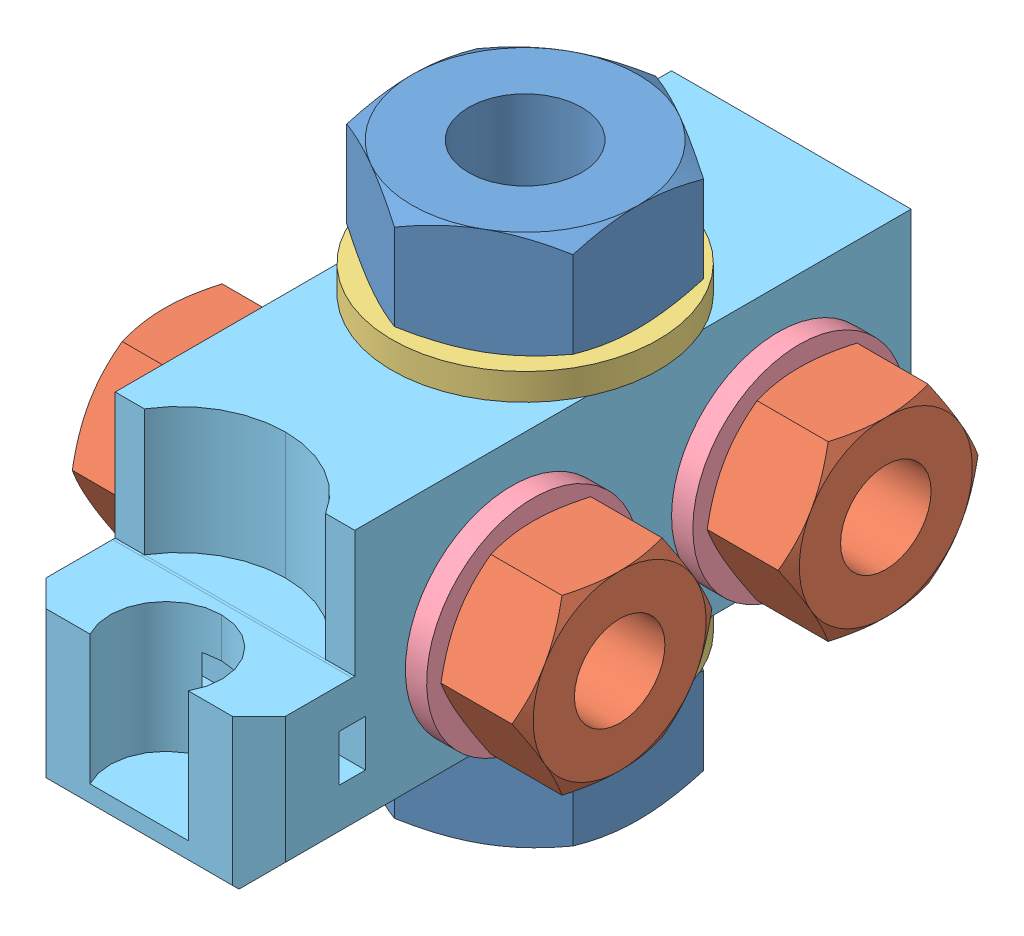
SolidWorks assembly Assembly y-corners, configuration Valor predeterminado. Lengths in mm.
Overall size (34.2 40 50.08).
13 component instances, 5 part files, 25 mates.
Components (placement in the parent):
- Nut DIN 934 - M10-1: Nut DIN 934 - M10 [Valor predeterminado] at (-49.2679 6.8342 8.2968) x (0 -1 0) z (0.866025 0 0.5) size (8 17 19.63)
- Nut DIN 934 - M8-1: Nut DIN 934 - M8 [Valor predeterminado] at (-63.1179 -10.1658 -1.7032) x (1 0 0) z (0 0.527567 0.849514) size (6.5 13 15.01)
- Washer DIN 125A - M10-1: Washer DIN 125A - M10 [Valor predeterminado] at (-49.2679 -19.1658 8.2968) x (0 -1 0) z (0.326363 0 0.945245) size (2 20 20)
- Washer DIN 125A - M8-1: Washer DIN 125A - M8 [Valor predeterminado] at (-40.2679 -10.1658 -1.7032) x (1 0 0) z (0 -0.550558 0.834797) size (1.6 16 16)
- Washer DIN 125A - M10-2: Washer DIN 125A - M10 [Valor predeterminado] at (-49.2679 2.8342 8.2968) x (0 -1 0) z (0.326363 0 0.945245) size (2 20 20)
- Washer DIN 125A - M8-2: Washer DIN 125A - M8 [Valor predeterminado] at (-59.8679 -10.1658 -1.7032) x (1 0 0) z (0 0.106248 0.99434) size (1.6 16 16)
- Nut DIN 934 - M10-2: Nut DIN 934 - M10 [Valor predeterminado] at (-49.2679 -25.1658 8.2968) x (0 -1 0) z (0.866025 0 0.5) size (8 17 19.63)
- Washer DIN 125A - M8-3: Washer DIN 125A - M8 [Valor predeterminado] at (-59.8679 -10.1658 18.2968) x (1 0 0) z (0 0.258445 0.966026) size (1.6 16 16)
- Washer DIN 125A - M8-4: Washer DIN 125A - M8 [Valor predeterminado] at (-40.2679 -10.1658 18.2968) x (1 0 0) z (0 -0.676712 0.736248) size (1.6 16 16)
- Nut DIN 934 - M8-2: Nut DIN 934 - M8 [Valor predeterminado] at (-63.1179 -10.1658 18.2968) x (1 0 0) z (0 0.866025 0.5) size (6.5 13 15.01)
- Nut DIN 934 - M8-3: Nut DIN 934 - M8 [Valor predeterminado] at (-35.4179 -10.1658 18.2968) x (1 0 0) z (0 0.866025 0.5) size (6.5 13 15.01)
- Nut DIN 934 - M8-4: Nut DIN 934 - M8 [Valor predeterminado] at (-35.4179 -10.1658 -1.7032) size (6.5 13 15.01)
- y-corners-2: y-corners [Valor predeterminado] at (-49.2679 0.8342 -11.7032) size (18 22 49)
Mates (geometry in assembly coordinates):
- Coincidente3: coincident: plane of assembly; plane of assembly; plane of Washer DIN 125A - M10-1 through (-49.2679 -21.1658 8.2968) normal (0 -1 0); plane of Nut DIN 934 - M10-2 through (-57.7679 -21.1658 -6.4256) normal (0 1 0)
- Coincidente4: coincident: plane of assembly; plane of assembly; plane of Nut DIN 934 - M10-1 through (-57.7679 2.8342 -6.4256) normal (0 -1 0); plane of Washer DIN 125A - M10-2 through (-49.2679 2.8342 8.2968) normal (0 1 0)
- Coincidente11: coincident: plane of assembly; plane of assembly; plane of Nut DIN 934 - M8-1 through (-59.8679 -14.1255 -8.0792) normal (1 0 0); plane of Washer DIN 125A - M8-2 through (-59.8679 -10.1658 -1.7032) normal (-1 0 0)
- Coincidente12: coincident: plane of assembly; plane of assembly; plane of Washer DIN 125A - M8-3 through (-59.8679 -10.1658 18.2968) normal (-1 0 0); plane of Nut DIN 934 - M8-2 through (-59.8679 -16.6658 14.5441) normal (1 0 0)
- Coincidente13: coincident: plane of assembly; plane of assembly; plane of Washer DIN 125A - M8-1 through (-38.6679 -10.1658 -1.7032) normal (1 0 0); plane of Nut DIN 934 - M8-4 through (-38.6679 -10.1658 -9.2087) normal (-1 0 0)
- Coincidente14: coincident: plane of assembly; plane of assembly; plane of Washer DIN 125A - M8-4 through (-38.6679 -10.1658 18.2968) normal (1 0 0); plane of Nut DIN 934 - M8-3 through (-38.6679 -16.6658 14.5441) normal (-1 0 0)
- Concêntrico1: concentric: cylinder of assembly; cylinder of assembly; cylinder of Washer DIN 125A - M8-3 through (-58.2679 -10.1658 18.2968) axis (-1 0 0) radius 4.2; cylinder of Nut DIN 934 - M8-2 through (-59.8679 -10.1658 18.2968) axis (-1 0 0) radius 3.4
- Concêntrico3: concentric: cylinder of assembly; cylinder of assembly; cylinder of Nut DIN 934 - M8-2 through (-59.8679 -10.1658 18.2968) axis (-1 0 0) radius 3.4; cylinder of y-corners-2 through (-65.2679 -10.1658 18.2968) axis (1 0 0) radius 4.4
- Coincidente15: coincident: plane of assembly; plane of assembly; plane of Washer DIN 125A - M8-3 through (-58.2679 -10.1658 18.2968) normal (1 0 0); plane of y-corners-2 through (-58.2679 -21.1658 -11.7032) normal (-1 0 0)
- Concêntrico4: concentric: cylinder of assembly; cylinder of assembly; cylinder of Nut DIN 934 - M8-1 through (-59.8679 -10.1658 -1.7032) axis (-1 0 0) radius 3.4; cylinder of Washer DIN 125A - M8-2 through (-58.2679 -10.1658 -1.7032) axis (-1 0 0) radius 4.2
- Concêntrico5: concentric: cylinder of assembly; cylinder of assembly; cylinder of Nut DIN 934 - M8-1 through (-59.8679 -10.1658 -1.7032) axis (-1 0 0) radius 3.4; cylinder of y-corners-2 through (-65.2679 -10.1658 -1.7032) axis (1 0 0) radius 4.4
- Coincidente16: coincident: plane of assembly; plane of assembly; plane of Washer DIN 125A - M8-2 through (-58.2679 -10.1658 -1.7032) normal (1 0 0); plane of y-corners-2 through (-58.2679 -21.1658 -11.7032) normal (-1 0 0)
- Concêntrico6: concentric: cylinder of assembly; cylinder of assembly; cylinder of Nut DIN 934 - M10-1 through (-49.2679 2.8342 8.2968) axis (0 1 0) radius 4.25; cylinder of Washer DIN 125A - M10-2 through (-49.2679 0.8342 8.2968) axis (0 1 0) radius 5.25
- Coincidente17: coincident: plane of assembly; plane of assembly; plane of Washer DIN 125A - M10-2 through (-49.2679 0.8342 8.2968) normal (0 -1 0); plane of y-corners-2 through (-58.2679 0.8342 -11.7032) normal (0 1 0)
- Concêntrico7: concentric: cylinder of assembly; cylinder of assembly; cylinder of Washer DIN 125A - M8-1 through (-38.6679 -10.1658 -1.7032) axis (-1 0 0) radius 4.2; cylinder of Nut DIN 934 - M8-4 through (-32.1679 -10.1658 -1.7032) axis (-1 0 0) radius 3.4
- Concêntrico8: concentric: cylinder of assembly; cylinder of assembly; cylinder of Washer DIN 125A - M8-4 through (-38.6679 -10.1658 18.2968) axis (-1 0 0) radius 4.2; cylinder of Nut DIN 934 - M8-3 through (-32.1679 -10.1658 18.2968) axis (-1 0 0) radius 3.4
- Concêntrico9: concentric: cylinder of assembly; cylinder of assembly; cylinder of Washer DIN 125A - M10-1 through (-49.2679 -21.1658 8.2968) axis (0 1 0) radius 5.25; cylinder of Nut DIN 934 - M10-2 through (-49.2679 -29.1658 8.2968) axis (0 1 0) radius 4.25
- Coincidente19: coincident: plane of assembly; plane of assembly; plane of Washer DIN 125A - M8-4 through (-40.2679 -10.1658 18.2968) normal (-1 0 0); plane of y-corners-2 through (-40.2679 -21.1658 -11.7032) normal (1 0 0)
- Coincidente20: coincident: plane of assembly; plane of assembly; plane of Washer DIN 125A - M8-1 through (-40.2679 -10.1658 -1.7032) normal (-1 0 0); plane of y-corners-2 through (-40.2679 -21.1658 -11.7032) normal (1 0 0)
- Coincidente21: coincident: plane of assembly; plane of assembly; plane of Washer DIN 125A - M10-2 through (-49.2679 0.8342 8.2968) normal (0 -1 0); plane of y-corners-2 through (-58.2679 0.8342 -11.7032) normal (0 1 0)
- Coincidente22: coincident: plane of assembly; plane of assembly; plane of Washer DIN 125A - M10-1 through (-49.2679 -19.1658 8.2968) normal (0 1 0); plane of y-corners-2 through (-49.2679 -19.1658 8.2968) normal (0 -1 0)
- Concêntrico10: concentric: cylinder of assembly; cylinder of assembly; cylinder of Nut DIN 934 - M8-4 through (-32.1679 -10.1658 -1.7032) axis (-1 0 0) radius 3.4; cylinder of y-corners-2 through (-65.2679 -10.1658 -1.7032) axis (1 0 0) radius 4.4
- Concêntrico11: concentric: cylinder of assembly; cylinder of assembly; cylinder of Nut DIN 934 - M8-3 through (-32.1679 -10.1658 18.2968) axis (-1 0 0) radius 3.4; cylinder of y-corners-2 through (-65.2679 -10.1658 18.2968) axis (1 0 0) radius 4.4
- Concêntrico12: concentric: cylinder of assembly; cylinder of assembly; cylinder of Nut DIN 934 - M10-1 through (-49.2679 2.8342 8.2968) axis (0 1 0) radius 4.25; cylinder of y-corners-2 through (-49.2679 -26.1658 8.2968) axis (0 1 0) radius 5.4
- Concêntrico13: concentric: cylinder of assembly; cylinder of assembly; cylinder of Nut DIN 934 - M10-2 through (-49.2679 -29.1658 8.2968) axis (0 1 0) radius 4.25; cylinder of y-corners-2 through (-49.2679 -26.1658 8.2968) axis (0 1 0) radius 5.4
